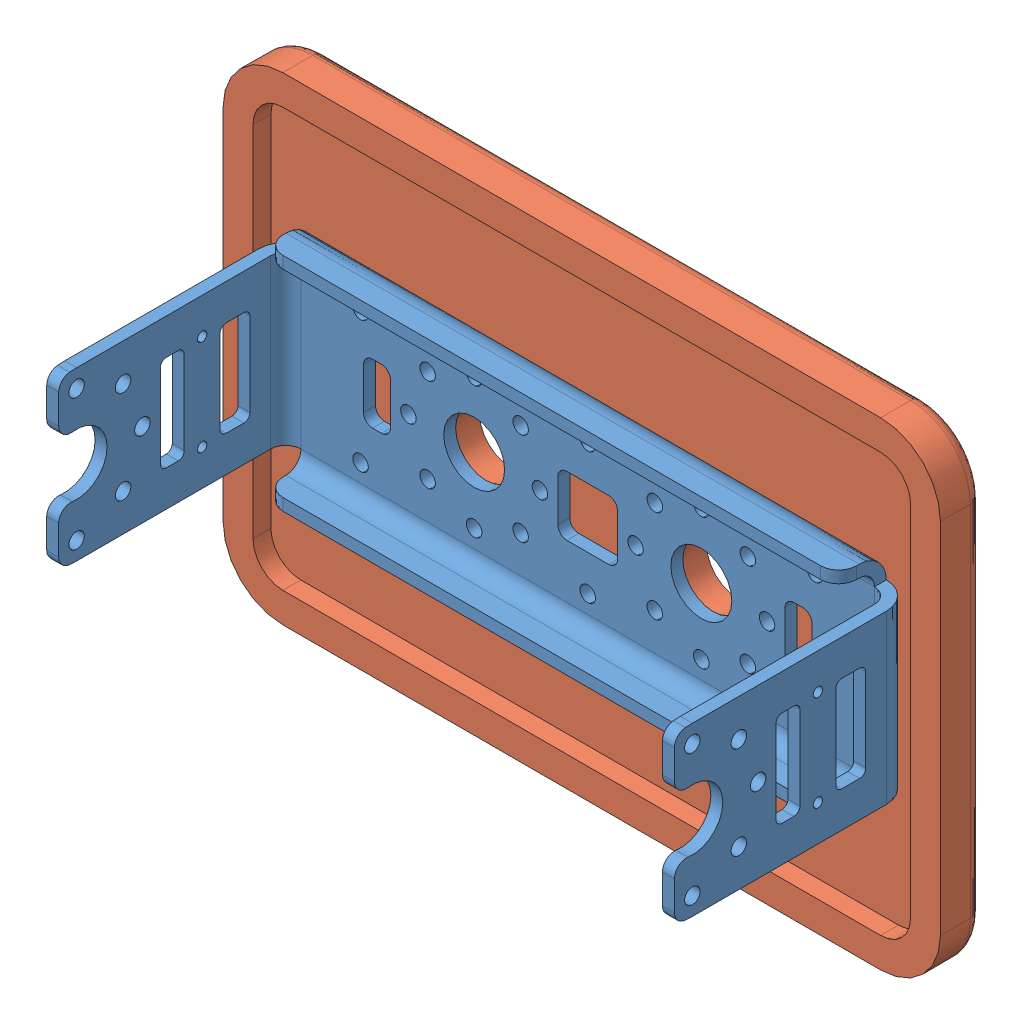
SolidWorks assembly leg_l6, configuration Default. Lengths in mm.
Overall size (120 80 44).
2 component instances, 2 part files, 3 mates.
Components (placement in the parent):
- HW-64106HXW_2017-1: HW-64106HXW_2017 [Default] at (-3.9692 33.4087 61.4394) size (105 37.08 40)
- foot_2017-1: foot_2017 [Default] at (44.5308 49.4087 57.4394) x (-1 0 0) z (0 1 0) size (120 7 80)
Mates (geometry in assembly coordinates):
- Concentric1: concentric aligned: cylinder of HW-64106HXW_2017-1 through (25.5308 49.4087 179.7606) axis (0 0 1) radius 5.1; cylinder of foot_2017-1 through (25.5308 49.4087 61.4394) axis (0 0 1) radius 5.1
- Concentric2: concentric aligned: cylinder of HW-64106HXW_2017-1 through (63.5308 49.4087 179.7606) axis (0 0 1) radius 5.1; cylinder of foot_2017-1 through (63.5308 49.4087 61.4394) axis (0 0 1) radius 5.1
- Coincident1: coincident anti-aligned: plane of HW-64106HXW_2017-1 through (69.7808 49.4087 61.4394) normal (0 0 -1); plane of foot_2017-1 through (44.5308 49.4087 61.4394) normal (0 0 1)
